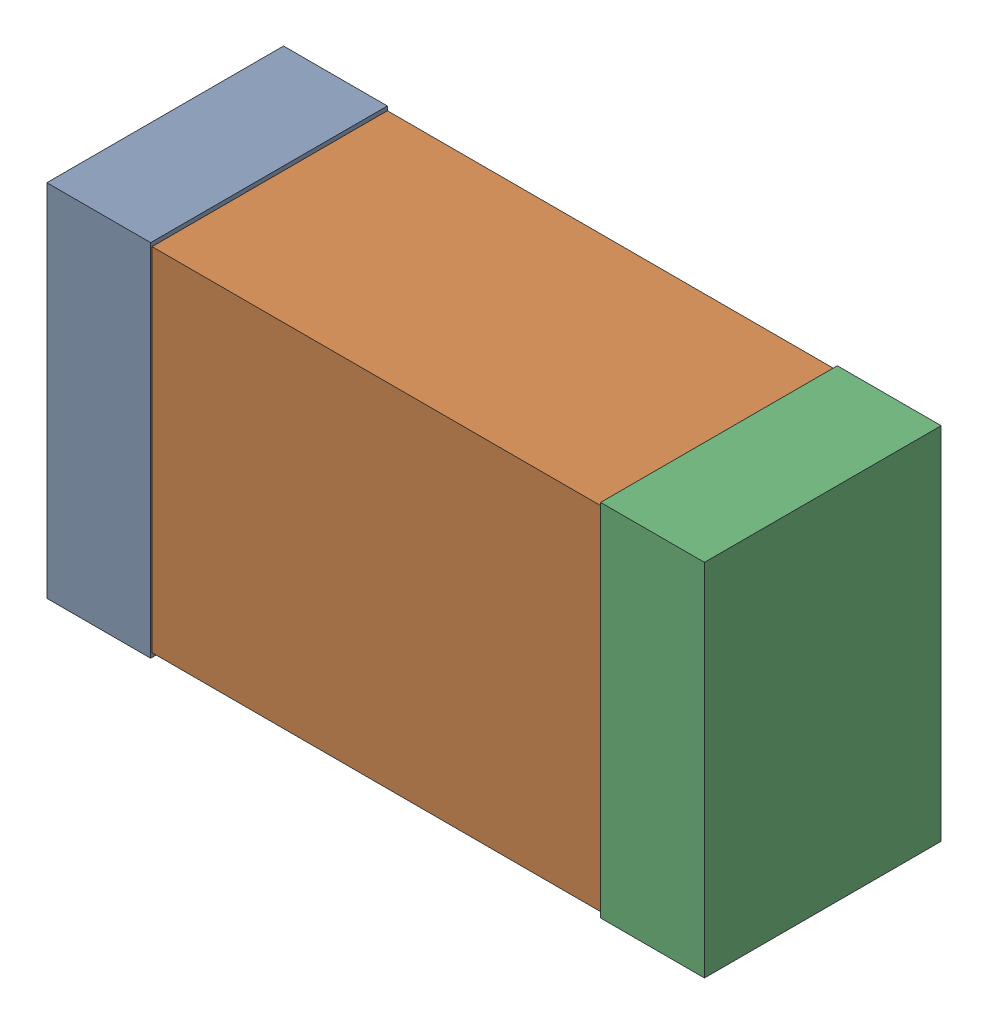
SolidWorks assembly C14_Motor_9Kanaloa_v2.0.0_Motor, configuration Default. Lengths in mm.
Overall size (2.38 1.3 0.85).
6 component instances, 2 part files, 0 mates.
Components (placement in the parent):
- 352877648-1: 352877648 [Default] at (34.009 166.624 0) size (0.38 1.3 0.85)
  - Extruded_14-1: Extruded_14 [Default] at origin size (0.38 1.3 0.85)
- 352877392-1: 352877392 [Default] at (35.009 166.624 0) size (2.2 1.27 0.85)
  - Extruded_15-1: Extruded_15 [Default] at origin size (2.2 1.27 0.85)
- 352877648-2: 352877648 [Default] at (36.009 166.624 0) size (0.38 1.3 0.85)
  - Extruded_14-1: Extruded_14 [Default] at origin size (0.38 1.3 0.85)
